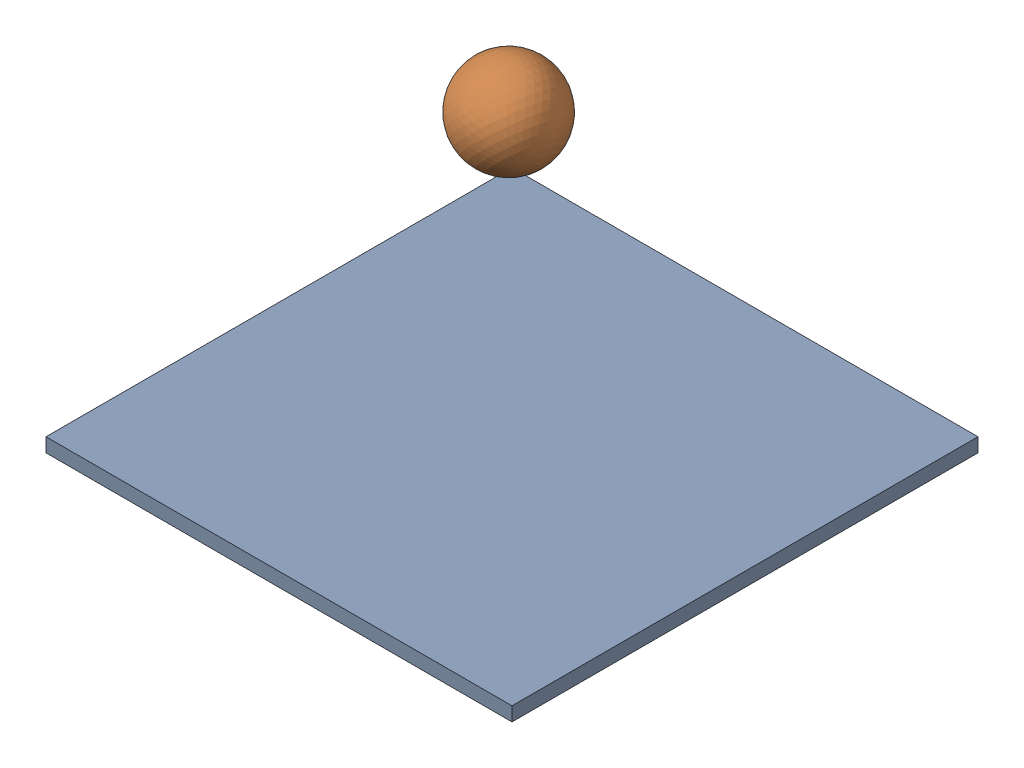
SolidWorks assembly ensamble, configuration Default. Lengths in mm.
Overall size (100 78.68 100).
2 component instances, 2 part files, 4 mates.
Components (placement in the parent):
- Placa-1: Placa [Default] at origin size (100 3 100)
- balin-1: balin [Default] at (-0.7359 63 -0.0133) x (0.192599 -0.023903 -0.980986) z (0.668183 0.735325 0.113268) size (20 20 20)
Mates (geometry in assembly coordinates):
- Coincident2: coincident anti-aligned: plane of Placa-1 through (0 0 0) normal (0 -1 0)
- Distance1: distance = 50 mm anti-aligned: plane of Placa-1 through (-50 3 -50) normal (0 0 -1)
- Distance2: distance = 50 mm aligned: plane of Placa-1 through (50 3 50) normal (1 0 0)
- Distance3: distance = 50 mm anti-aligned: sphere of balin-1; plane of Placa-1 through (0 3 0) normal (0 1 0)
